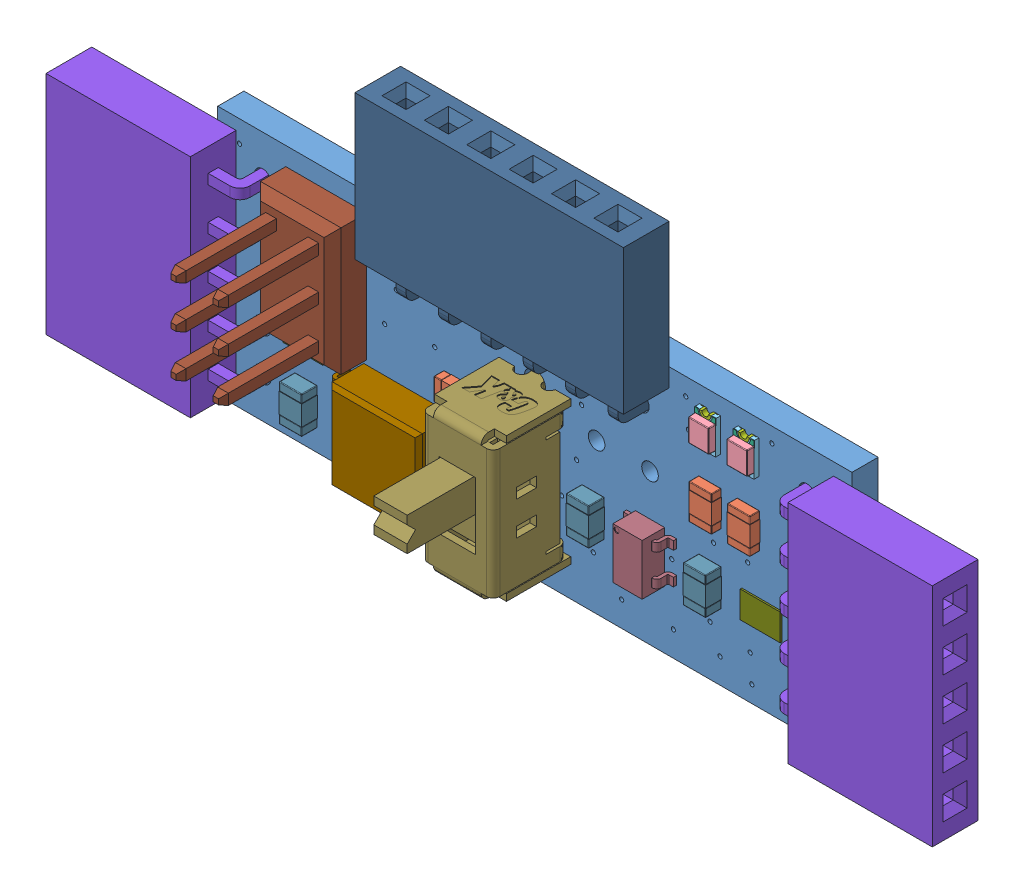
SolidWorks assembly remotePCB, configuration Default. Lengths in mm.
Overall size (53.1 22.55 11.8).
32 component instances, 16 part files, 0 mates.
Components (placement in the parent):
- PCB Component-1: PCB Component [Default] at origin size (53.1 22.55 11.8)
  - Board-1: Board [Default] at origin size (38 15 1.57)
  - 1K-1: 1K [Default] at (14.6 7.4 1.57) x (-1 0 0) z (0 0 1) size (2.11 1.36 0.61)
  - 1K-2: 1K [Default] at (29.5 9.2 1.57) x (0 1 0) z (0 0 1) size (2.11 1.36 0.61)
  - 1K-3: 1K [Default] at (31.8 9.2 1.57) x (0 1 0) z (0 0 1) size (2.11 1.36 0.61)
  - GREEN-1: GREEN [Default] at (29.5 13 1.57) x (0 -1 0) z (0 0 1) size (2 1.25 0.7)
    - base-1: base [Default] at (0.8 0 0) x (-1 0 0) z (0 0 1) size (0.4 1 0.3)
    - cover-1: cover [Default] at (0 0 0.3) size (1.4 1.25 0.4)
    - housing-1: housing [Default] at origin size (2 1.25 0.3)
    - marking-1: marking [Default] at (-0.8 0.525 0.26) size (0.4 0.48 0.04)
    - marking-2: marking [Default] at (-0.8 -0.525 0.3) x (1 0 0) z (0 0 -1) size (0.4 0.48 0.04)
    - base_2-1: base_2 [Default] at (-0.8 0 0) size (0.4 1 0.3)
  - GREEN-2: GREEN [Default] at (31.8 13 1.57) x (0 -1 0) z (0 0 1) size (2 1.25 0.7)
    - base-1: base [Default] at (0.8 0 0) x (-1 0 0) z (0 0 1) size (0.4 1 0.3)
    - cover-1: cover [Default] at (0 0 0.3) size (1.4 1.25 0.4)
    - housing-1: housing [Default] at origin size (2 1.25 0.3)
    - marking-1: marking [Default] at (-0.8 0.525 0.26) size (0.4 0.48 0.04)
    - marking-2: marking [Default] at (-0.8 -0.525 0.3) x (1 0 0) z (0 0 -1) size (0.4 0.48 0.04)
    - base_2-1: base_2 [Default] at (-0.8 0 0) size (0.4 1 0.3)
  - Thumbstick-1: Thumbstick [Default] at (2.7 12.6 1.57) x (0 -1 0) z (0 0 1) size (13.55 10.55 5.89)
  - Thumbstick-2: Thumbstick [Default] at (35.3 2.4 1.57) x (0 1 0) z (0 0 1) size (13.55 10.55 5.89)
  - ATtiny85V-1: ATtiny85V [Default] at (11.5 3.4 1.57) x (-1 0 0) z (0 0 1) size (8.26 5.35 2.16)
  - HM-10-1: HM-10 [Default] at (25.35 12.3 1.57) x (-1 0 0) z (0 0 1) size (16.09 10.55 5.89)
  - PTH VERT MALE-1: PTH VERT MALE [Default] at (5.73 8.06 1.57) x (0 1 0) z (0 0 1) size (7.62 4.83 11.43)
  - 300mA_30V-1: 300mA_30V [Default] at (19 6.1 1.57) size (4.3 8.6 11.5)
  - MCP1802 300mA_3.3V-1: MCP1802 300mA_3.3V [Default] at (26 5.1 1.57) size (3 3.05 1.45)
  - 1uF_25V-1: 1uF_25V [Default] at (5.3 2.4 1.57) x (0 1 0) z (0 0 1) size (2.21 1.36 0.96)
  - 1uF_25V-2: 1uF_25V [Default] at (29.5 5.1 1.57) x (0 -1 0) z (0 0 1) size (2.21 1.36 0.96)
  - 1uF_25V-3: 1uF_25V [Default] at (22.5 5.2 1.57) x (0 -1 0) z (0 0 1) size (2.21 1.36 0.96)
  - BATTERY_LIPO_2S-1: BATTERY_LIPO_2S [Default] at (24.3 9 0) x (1 0 0) z (0 0 -1) size (6 3.45 0.1)
  - JUMPER_SMD_3-PAD_NO_SILK-1: JUMPER_SMD_3-PAD_NO_SILK [Default] at (32.6 4.9 1.57) size (2.4 1.6 0.1)
  - JUMPER_SMD_3-PAD_NO_SILK-2: JUMPER_SMD_3-PAD_NO_SILK [Default] at (5.2 5.6 1.57) size (2.4 1.6 0.1)
